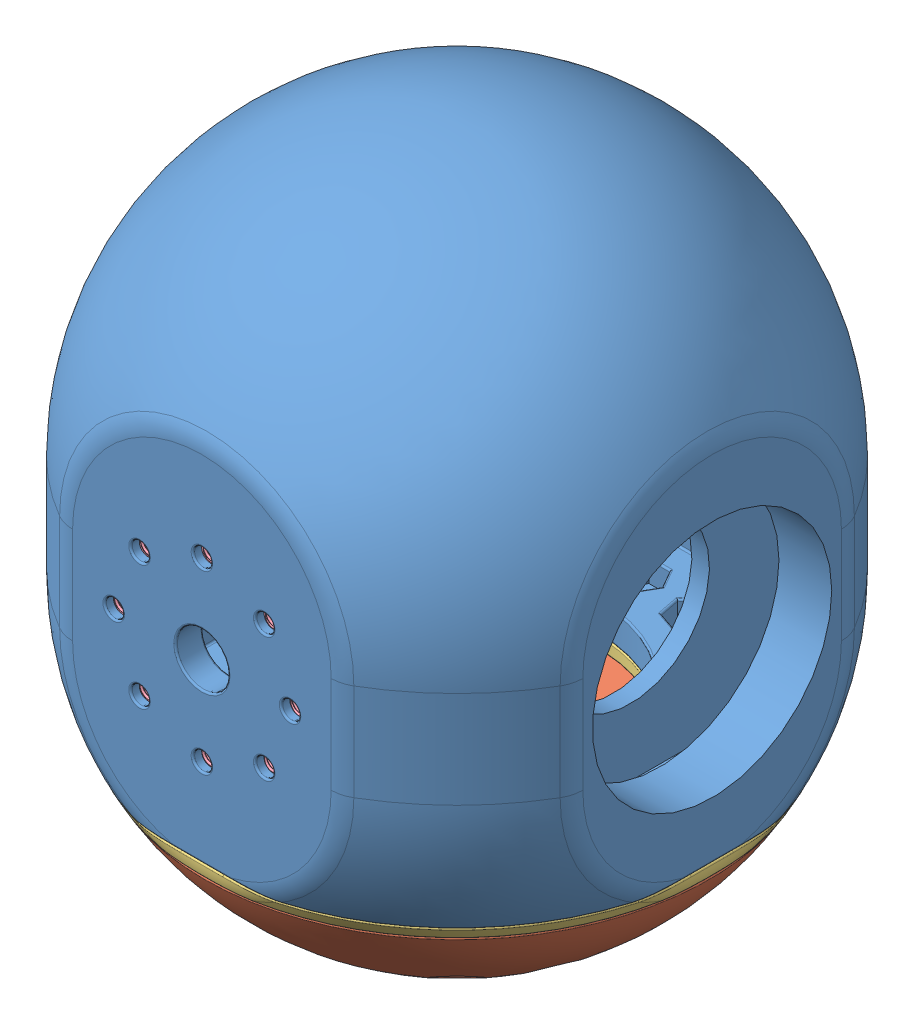
SolidWorks assembly Main_Body_Assembly, configuration Default. Lengths in mm.
Overall size (149.49 192.5 149.49).
21 component instances, 6 part files, 19 mates.
Components (placement in the parent):
- Main_Top-1: Main_Top [Default] at origin size (148.79 147.08 148.79)
- Main_Bottom-1: Main_Bottom [Default] at origin size (143.6 42.5 143.6)
- Main_Seal-1: Main_Seal [Default] at origin size (149.49 6.96 149.49)
- Arm_Static_Nut-1: Arm_Static_Nut [Default] at (0 25.0625 -70) x (1 0 0) z (0 -1 0) size (9.16 5.42 8)
- Arm_Static_Nut-2: Arm_Static_Nut [Default] at (0 25.0625 70) x (1 0 0) z (0 1 0) size (9.16 5.42 8)
- Arm_Static_Nut-3: Arm_Static_Nut [Default] at (-17.7219 17.7219 70) x (0.707107 0.707107 0) z (-0.707107 0.707107 0) size (9.16 5.42 8)
- Arm_Static_Nut-4: Arm_Static_Nut [Default] at (-25.0625 0 70) x (0 1 0) z (-1 0 0) size (9.16 5.42 8)
- Arm_Static_Nut-5: Arm_Static_Nut [Default] at (-17.7219 -17.7219 70) x (-0.707107 0.707107 0) z (-0.707107 -0.707107 0) size (9.16 5.42 8)
- Arm_Static_Nut-6: Arm_Static_Nut [Default] at (0 -25.0625 70) x (-1 0 0) z (0 -1 0) size (9.16 5.42 8)
- Arm_Static_Nut-7: Arm_Static_Nut [Default] at (17.7219 -17.7219 70) x (-0.707107 -0.707107 0) z (0.707107 -0.707107 0) size (9.16 5.42 8)
- Arm_Static_Nut-8: Arm_Static_Nut [Default] at (25.0625 0 70) x (0 -1 0) z (1 0 0) size (9.16 5.42 8)
- Arm_Static_Nut-9: Arm_Static_Nut [Default] at (17.7219 17.7219 70) x (0.707107 -0.707107 0) z (0.707107 0.707107 0) size (9.16 5.42 8)
- Arm_Static_Nut-10: Arm_Static_Nut [Default] at (-17.7219 17.7219 -70) x (0.707107 0.707107 0) z (0.707107 -0.707107 0) size (9.16 5.42 8)
- Arm_Static_Nut-11: Arm_Static_Nut [Default] at (-25.0625 0 -70) x (0 1 0) z (1 0 0) size (9.16 5.42 8)
- Arm_Static_Nut-12: Arm_Static_Nut [Default] at (-17.7219 -17.7219 -70) x (-0.707107 0.707107 0) z (0.707107 0.707107 0) size (9.16 5.42 8)
- Arm_Static_Nut-13: Arm_Static_Nut [Default] at (0 -25.0625 -70) x (-1 0 0) z (0 1 0) size (9.16 5.42 8)
- Arm_Static_Nut-14: Arm_Static_Nut [Default] at (17.7219 -17.7219 -70) x (-0.707107 -0.707107 0) z (-0.707107 0.707107 0) size (9.16 5.42 8)
- Arm_Static_Nut-15: Arm_Static_Nut [Default] at (25.0625 0 -70) x (0 -1 0) z (-1 0 0) size (9.16 5.42 8)
- Arm_Static_Nut-16: Arm_Static_Nut [Default] at (17.7219 17.7219 -70) x (0.707107 -0.707107 0) z (-0.707107 -0.707107 0) size (9.16 5.42 8)
- Nema_8_Short-1: Nema_8_Short [Default] at (-44.25 26.875 0) x (0 0.707107 0.707107) z (0 -0.707107 0.707107) size (22 40 20)
- Nema_Gear-2: Nema_Gear [Default] at (-51 26.875 0) x (0 0.707107 -0.707107) z (0 -0.707107 -0.707107) size (14.96 10.01 14.93)
Mates (geometry in assembly coordinates):
- Coincident12: coincident: plane of Main_Top-1 through (0 -50 0) normal (0 -1 0); plane of Main_Seal-1 through (0 -50 0) normal (0 1 0)
- Coincident13: coincident: plane of Main_Bottom-1 through (0 -53.75 0) normal (0 1 0); plane of Main_Seal-1 through (0 -53.75 0) normal (0 -1 0)
- Concentric15: concentric: circle of Main_Bottom-1; cylinder of Main_Seal-1 through (0 -96.25 0) axis (0 1 0) radius 40
- Concentric16: concentric: cylinder of Main_Top-1 through (0 -41.5 0) axis (0 -1 0) radius 40; cylinder of Main_Seal-1 through (0 -96.25 0) axis (0 1 0) radius 40
- Coincident15: coordinate: point of ?
- Coincident16: coincident: plane of Main_Top-1 through (0 0 0) normal (0 1 0); plane of assembly through (0 0 0) normal (0 1 0)
- Coincident17: coincident: plane of Main_Top-1 through (0 0 0) normal (0 0 1); plane of assembly through (0 0 0) normal (0 0 1)
- Coincident18: coincident: plane of Main_Top-1 through (0 0 0) normal (1 0 0); plane of assembly through (0 0 0) normal (1 0 0)
- Concentric21: concentric: cylinder of Main_Top-1 through (0 25.0625 -72.5) axis (0 0 1) radius 2.5625; cylinder of Arm_Static_Nut-1 through (0 25.0625 -65.5) axis (0 0 1) radius 2.5
- Coincident23: coincident: plane of Main_Top-1 through (0 0 -70) normal (0 0 1); plane of Arm_Static_Nut-1 through (0 25.0625 -70) normal (0 0 -1)
- Concentric22: concentric: cylinder of Main_Top-1 through (0 25.0625 -72.5) axis (0 0 1) radius 2.5625; cylinder of Arm_Static_Nut-2 through (0 25.0625 65.5) axis (0 0 -1) radius 2.5
- Coincident24: coincident: plane of Main_Top-1 through (0 0 70) normal (0 0 -1); plane of Arm_Static_Nut-2 through (0 25.0625 70) normal (0 0 1)
- Parallel1: parallel: plane of Arm_Static_Nut-1 through (2.3094 29.0625 -66.8) normal (0 1 0); plane of assembly through (0 0 0) normal (0 1 0)
- Distance1: distance = 0.25 mm: plane of Nema_Gear-2 through (-46 26.875 0) normal (1 0 0); plane of Nema_8_Short-1 through (-45.75 26.875 0) normal (-1 0 0)
- Concentric23: concentric: cylinder of Nema_8_Short-1 through (-54.25 26.875 0) axis (1 0 0) radius 2; cylinder of Nema_Gear-2 through (-56.0053 26.875 0) axis (1 0 0) radius 2.1875
- Coincident32: coincident: plane of Main_Top-1 through (-44.25 96.251 -60.2453) normal (1 0 0); plane of Nema_8_Short-1 through (-44.25 26.875 0) normal (-1 0 0)
- Parallel4: parallel: plane of Nema_8_Short-1 through (-54.25 35.0067 -6.0104) normal (0 0.707107 0.707107); plane of Nema_Gear-2 through (-43.1716 27.084 2.1775) normal (0 -0.707107 -0.707107)
- Concentric24: concentric: cylinder of Main_Top-1 through (86.6451 26.875 10.8894) axis (-1 0 0) radius 1.125; cylinder of Nema_8_Short-1 through (-41.75 26.875 10.8894) axis (-1 0 0) radius 1
- Concentric25: concentric: cylinder of Main_Top-1 through (86.6451 26.875 -10.8894) axis (-1 0 0) radius 1.125; cylinder of Nema_8_Short-1 through (-41.75 26.875 -10.8894) axis (-1 0 0) radius 1
